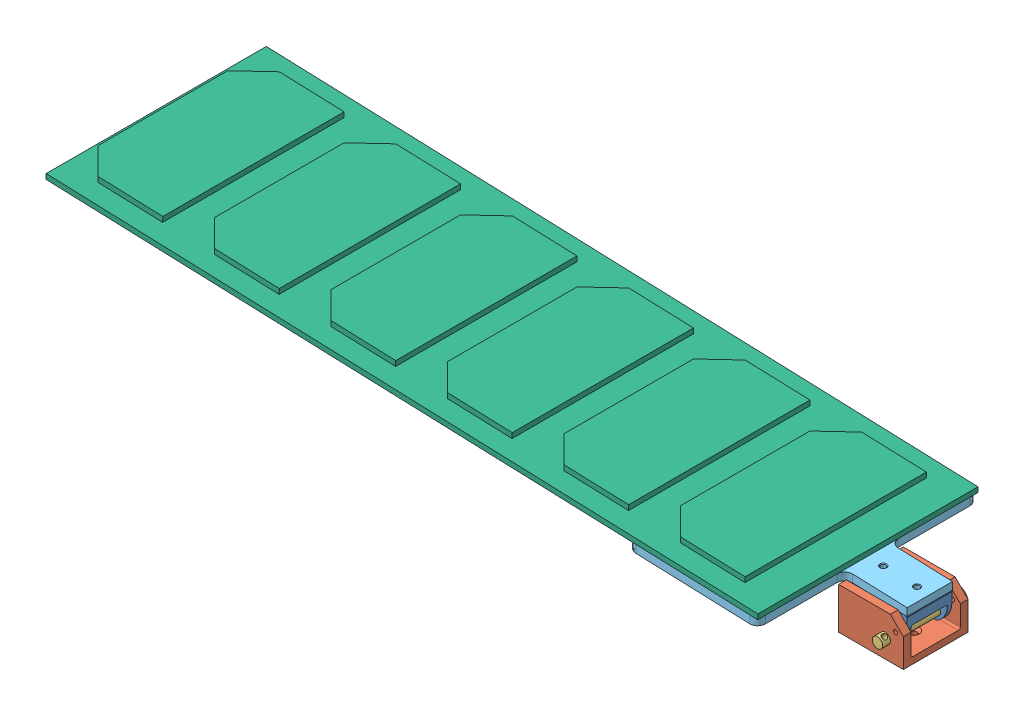
SolidWorks assembly Bracket_Assembly_V1, configuration Default. Lengths in mm.
Overall size (300.92 32.54 85).
9 component instances, 7 part files, 16 mates.
Components (placement in the parent):
- Swing_Piece_V1-1: Swing_Piece_V1 [Default] at (-1.5218 9.4629 11.8718) x (0.035825 0.999358 0) z (0 0 1) size (11.5 22.34 17.5)
- Base better redesign-1: Base better redesign [Default] at (1.9122 2.865 20.4718) x (1 0 0) z (0 -1 0) size (25 25 16)
- Bolt_mcmaster_V1-1: Bolt_mcmaster_V1 [93217A290] at (7.4122 7.365 129.9718) x (0.866515 -0.49915 0) z (0 0 1) size (8 8 31)
- Locking_Pin_mcmaster_V1-1: Locking_Pin_mcmaster_V1 [98378A149] at (3.558 11.5058 -18.0282) x (-0.894491 0.447087 0) z (0 0 -1) size (3 3 7)
- 9271K88_Torsion Spring-1: 9271K88_Torsion Spring [9271K88] at (7.691 7.499 23.983) x (0.159653 -0.022827 -0.986909) z (-0.95932 -0.239394 -0.149653) size (4.03 5.49 38.1) (hidden)
- 9271K88_Torsion Spring-3: 9271K88_Torsion Spring [9271K88] at (7.1421 7.2576 15.5875) x (-0.070231 -0.093274 -0.99316) z (-0.995192 0.074684 0.06336) size (4.03 5.49 38.1) (hidden)
- Locking_Pin_mcmaster_V1-3: Locking_Pin_mcmaster_V1 [98378A149] at (3.558 11.5058 58.9718) x (0.595621 -0.803266 0) z (0 0 1) size (3 3 7)
- Array HolderV2-1: Array HolderV2 [Default] at (-11.7887 16.0585 20.6218) x (0 0 -1) z (0.999358 -0.035825 0) size (85 3 74)
- Solar Panel-1: Solar Panel [Default] at (-149.093 23.9825 20.6218) x (0.999358 -0.035825 0) z (0 0 1) size (275 4 85)
Mates (geometry in assembly coordinates):
- Concentric1: concentric anti-aligned: cylinder of Hinge mcmaster 4mm-1 through (7.4122 7.365 254.9718) axis (0 0 1) radius 2; cylinder of Base better redesign-1 through (7.4122 7.365 32.9718) axis (0 0 -1) radius 2
- Coincident2: coincident anti-aligned: plane of Base better redesign-1 through (-10.5878 0.365 7.9718) normal (0 0 -1); plane of Hinge mcmaster 4mm-1 through (9.4088 10.8311 7.9718) normal (0 0 1)
- Concentric2: concentric anti-aligned: cylinder of Swing_Piece_V1-1 through (7.4122 7.365 29.3718) axis (0 0 -1) radius 2; cylinder of Hinge mcmaster 4mm-1 through (7.4122 7.365 254.9718) axis (0 0 1) radius 2
- Distance1: distance = 0.6 mm anti-aligned: plane of Swing_Piece_V1-1 through (-1.5218 9.4629 29.3718) normal (0 0 1); plane of Base better redesign-1 through (-10.5878 16.365 29.9718) normal (0 0 -1)
- Concentric4: concentric anti-aligned: cylinder of Swing_Piece_V1-1 through (3.558 11.5058 18.8718) axis (0 0 -1) radius 1.5; cylinder of Locking_Pin_mcmaster_V1-1 through (3.558 11.5058 15.9718) axis (0 0 1) radius 1.5
- Coincident5: coincident anti-aligned: plane of Base better redesign-1 through (-10.5878 16.365 10.9718) normal (0 0 1); plane of Locking_Pin_mcmaster_V1-1 through (4.0051 12.4002 10.9718) normal (0 0 -1)
- Tangent6: tangent anti-aligned: cylinder of Bolt_mcmaster_V1-1 through (7.4122 7.365 254.9718) axis (0 0 1) radius 2; face of 9271K88_Torsion Spring-1
- Concentric6: concentric anti-aligned: cylinder of Swing_Piece_V1-1 through (3.558 11.5058 22.3718) axis (0 0 1) radius 1.5; cylinder of Locking_Pin_mcmaster_V1-3 through (3.558 11.5058 24.9718) axis (0 0 -1) radius 1.5
- Coincident6: coincident anti-aligned: plane of Base better redesign-1 through (-10.5878 16.365 29.9718) normal (0 0 -1); plane of Locking_Pin_mcmaster_V1-3 through (4.3613 12.1014 29.9718) normal (0 0 1)
- Coincident14: coincident aligned: plane of Array HolderV2-1 through (-11.6813 19.0565 -21.8782) normal (0 0 -1); plane of Solar Panel-1 through (-286.4331 30.9071 -21.8782) normal (0 0 -1)
- Coincident15: coincident anti-aligned: plane of Swing_Piece_V1-1 through (14.6943 15.1091 29.3718) normal (0.035825 0.999358 0); plane of Array HolderV2-1 through (-11.7887 16.0585 20.6218) normal (-0.035825 -0.999358 0)
- Coincident17: coincident aligned: line of Array HolderV2-1 through (-11.6813 19.0565 60.1218) axis (0 0 -1); line of Solar Panel-1 through (-11.6813 19.0565 63.1218) axis (0 0 -1)
- Coincident18: coincident anti-aligned: plane of Array HolderV2-1 through (-11.6813 19.0565 20.6218) normal (0.035825 0.999358 0); plane of Solar Panel-1 through (-149.093 23.9825 20.6218) normal (-0.035825 -0.999358 0)
- Coincident19: coincident aligned: plane of Array HolderV2-1 through (-61.6492 20.8478 63.1218) normal (0 0 1); plane of Solar Panel-1 through (-286.4331 30.9071 63.1218) normal (0 0 1)
- Coincident20: coincident aligned: plane of Swing_Piece_V1-1 through (12.1959 15.1987 29.3718) normal (0.999358 -0.035825 0); plane of Array HolderV2-1 through (11.1318 -14.485 29.3718) normal (0.999358 -0.035825 0)
- Coincident21: coincident aligned: plane of Swing_Piece_V1-1 through (-1.5218 9.4629 11.8718) normal (0 0 -1); plane of Array HolderV2-1 through (11.1318 -14.485 11.8718) normal (0 0 -1)
